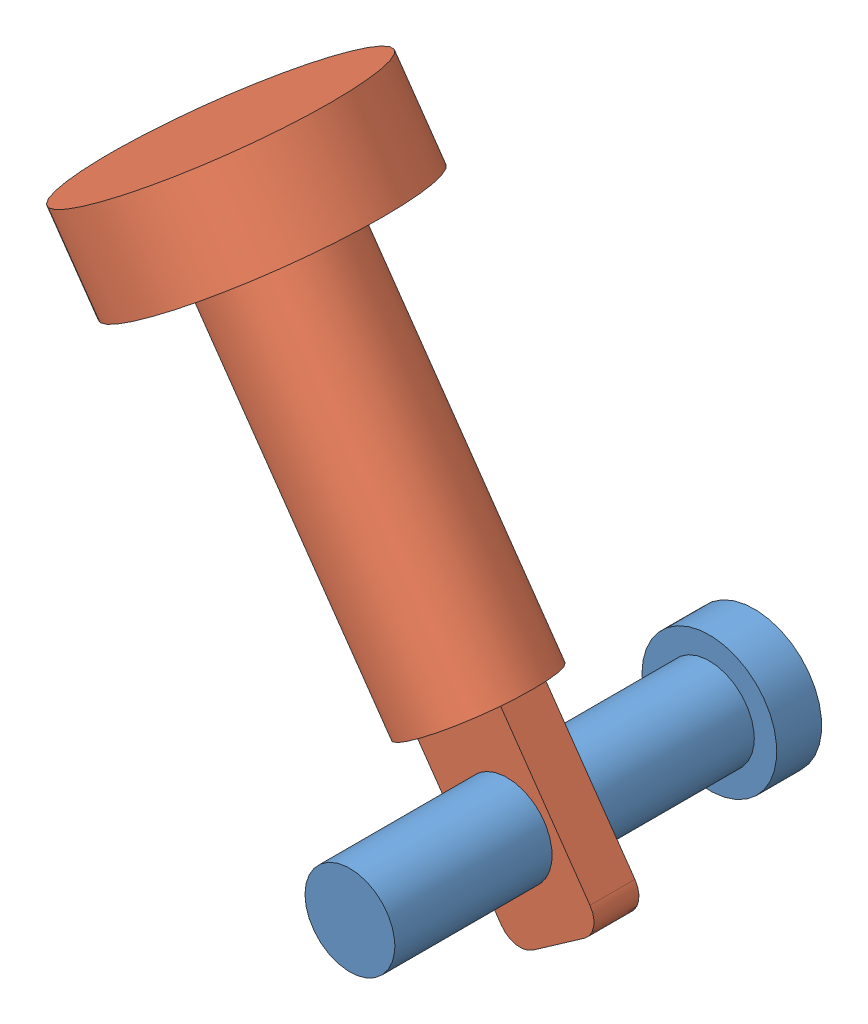
SolidWorks assembly front_axle, configuration Default. Lengths in mm.
Overall size (164.35 189.37 114.3).
2 component instances, 2 part files, 5 mates.
Components (placement in the parent):
- pin_for_front_wheel-1: pin_for_front_wheel [Default] at origin size (38.1 38.1 114.3)
- front_wheel_axle-1: front_wheel_axle [Default] at (-80.0743 114.4736 57.15) x (-0.819424 -0.573187 0) z (0.573187 -0.819424 0) size (76.2 76.2 177.8)
Mates (geometry in assembly coordinates):
- Coincident1: coincident aligned: plane of pin_for_front_wheel-1 through (0 0 0) normal (0 0 1)
- Coincident2: coincident aligned: plane of pin_for_front_wheel-1 through (0 0 0) normal (1 0 0)
- Coincident3: coincident aligned: plane of pin_for_front_wheel-1 through (0 0 0) normal (0 1 0)
- Concentric1: concentric aligned: cylinder of pin_for_front_wheel-1 through (0 0 107.95) axis (0 0 -1) radius 12.7; cylinder of front_wheel_axle-1 through (0 0 95.25) axis (0 0 -1) radius 12.7
- Distance1: distance = 57.15 mm aligned: plane of front_wheel_axle-1 through (27.047 -12.078 50.8) normal (0 0 -1); plane of pin_for_front_wheel-1 through (0 0 -6.35) normal (0 0 -1)
